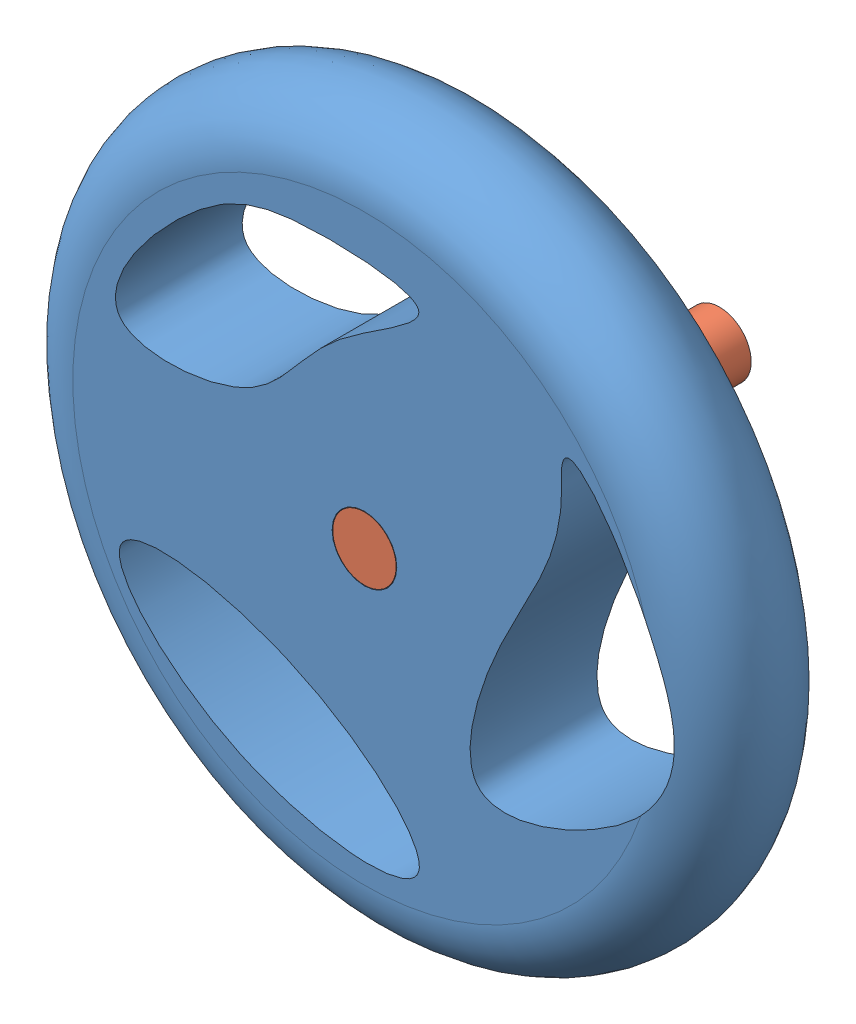
SolidWorks assembly Volante, configuration Predeterminado. Lengths in mm.
Overall size (392 392 196.03).
2 component instances, 2 part files, 2 mates.
Components (placement in the parent):
- volante-1: volante [Predeterminado] at (-15.6016 4.4639 -1.7053) size (392 392 76.66)
- buje-1: buje [Predeterminado] at (-11.7362 2.6514 -73.7054) size (35 35 196)
Mates (geometry in assembly coordinates):
- Concéntrica1: concentric: cylinder of assembly; line of assembly; cylinder of volante-1 through (-11.7362 2.6514 38.2946) axis (0 0 -1) radius 17.85; axis of buje-1 through (-11.7362 2.6514 38.2946) axis (0 0 -1)
- Coincidente1: coincident aligned: plane of volante-1 through (-11.7362 2.6514 38.2946) normal (0 0 1); plane of buje-1 through (-11.7362 2.6514 38.2946) normal (0 0 1)
